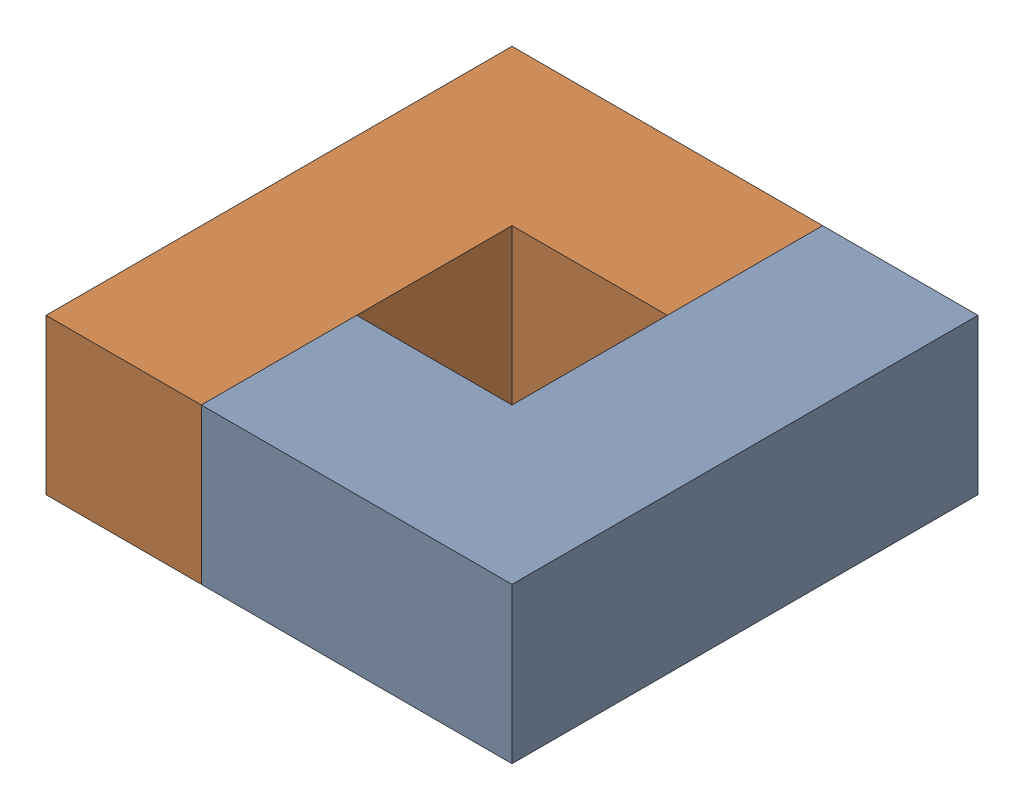
SolidWorks assembly Assem3, configuration Default. Lengths in mm.
Overall size (90 30 90).
2 component instances, 1 part files, 1 mates.
Components (placement in the parent):
- task2Part1-1: task2Part1 [Default] at (54.3963 11.6731 83.9325) x (0 0 -1) z (0 1 0) size (90 60 30)
- task2Part1-2: task2Part1 [Default] at (-35.6037 11.6731 -6.0675) x (0 0 1) z (0 1 0) size (90 60 30)
Mates (geometry in assembly coordinates):
- Coincident16: coincident: point of task2Part1-1; point of task2Part1-2
